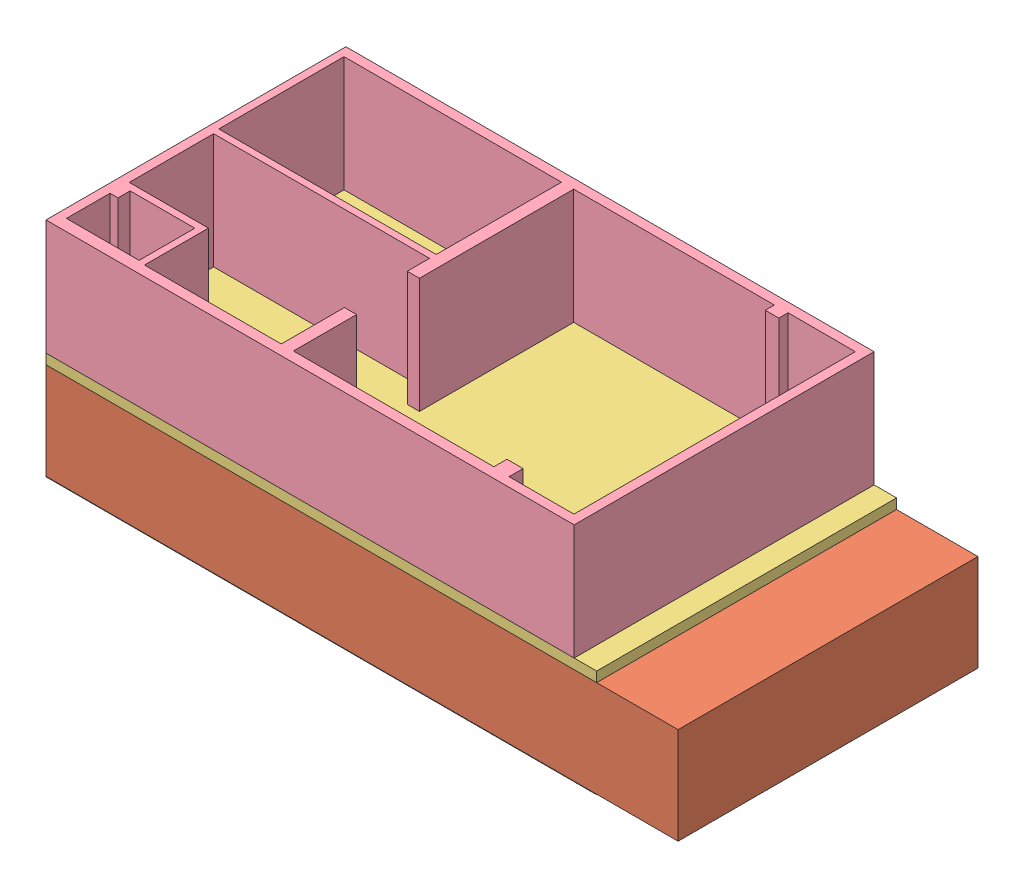
SolidWorks assembly Wohnung, configuration Standard. Lengths in mm.
Overall size (13774.89 4849 6536).
4 component instances, 4 part files, 12 mates.
Components (placement in the parent):
- UG-Boden-1: UG-Boden [Standard] at (0 -2335 6536) size (12000 10 6536)
- UG-Wände-1: UG-Wände [Standard] at (0 -2325 6536) size (13774.89 2106 6536)
- EG-Boden-1: EG-Boden [Standard] at (0 -219 6536) size (12000 219 6536)
- EG-Wände-1: EG-Wände [Standard] at (194 0 6285) size (11510.21 2514 6536)
Mates (geometry in assembly coordinates):
- Deckungsgleich1: coincident aligned: plane of UG-Boden-1 through (0 -2325 6536) normal (0 0 1); plane of UG-Wände-1 through (0 -219 6536) normal (0 0 1)
- Deckungsgleich2: coincident anti-aligned: plane of UG-Boden-1 through (0 -2325 6536) normal (0 1 0); plane of UG-Wände-1 through (0 -2325 6536) normal (0 -1 0)
- Deckungsgleich3: coincident aligned: plane of UG-Boden-1 through (0 -2325 6536) normal (-1 0 0); plane of UG-Wände-1 through (0 -219 6536) normal (-1 0 0)
- Deckungsgleich4: coincident anti-aligned: plane of UG-Wände-1 through (0 -219 6536) normal (0 1 0); plane of EG-Boden-1 through (0 -219 6536) normal (0 -1 0)
- Deckungsgleich5: coincident aligned: plane of UG-Wände-1 through (0 -219 6536) normal (0 0 1); plane of EG-Boden-1 through (0 0 6536) normal (0 0 1)
- Deckungsgleich6: coincident aligned: plane of UG-Wände-1 through (0 -219 6536) normal (-1 0 0); plane of EG-Boden-1 through (0 0 6536) normal (-1 0 0)
- Deckungsgleich7: coincident aligned: plane of EG-Boden-1 through (0 0 6536) normal (0 1 0); plane of assembly through (0 0 0) normal (0 1 0)
- Deckungsgleich8: coincident anti-aligned: plane of UG-Boden-1 through (0 -2325 0) normal (0 0 -1); plane of assembly through (0 0 0) normal (0 0 1)
- Deckungsgleich9: coincident anti-aligned: plane of UG-Boden-1 through (0 -2325 6536) normal (-1 0 0); plane of assembly through (0 0 0) normal (1 0 0)
- Deckungsgleich10: coincident: plane of EG-Boden-1 through (0 0 6536) normal (0 1 0); plane of EG-Wände-1 through (1055.9802 0 6285) normal (0 -1 0)
- Deckungsgleich13: coincident: plane of EG-Boden-1 through (0 0 6536) normal (0 0 1); plane of EG-Wände-1 through (0 2514 6536) normal (0 0 1)
- Deckungsgleich14: coincident aligned: plane of EG-Boden-1 through (0 0 6536) normal (-1 0 0); plane of EG-Wände-1 through (0 2514 6536) normal (-1 0 0)
